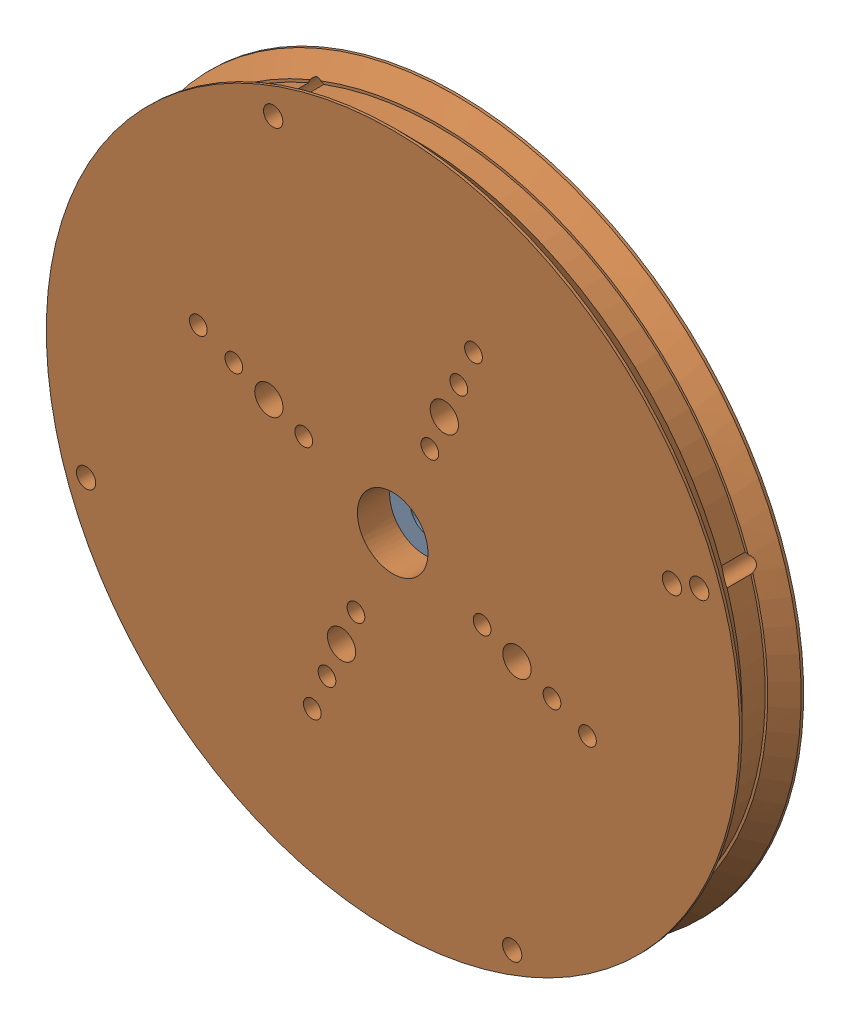
SolidWorks assembly poulie fil, configuration Défaut. Lengths in mm.
Overall size (54 54 8.43).
2 component instances, 2 part files, 0 mates.
Components (placement in the parent):
- poulie servo-1: poulie servo [Default] at origin size (34.37 34.8 5.82)
- poulie ronde-1: poulie ronde [Défaut] at (-0.2408 3.1103 0.1383) size (54 54 5)
